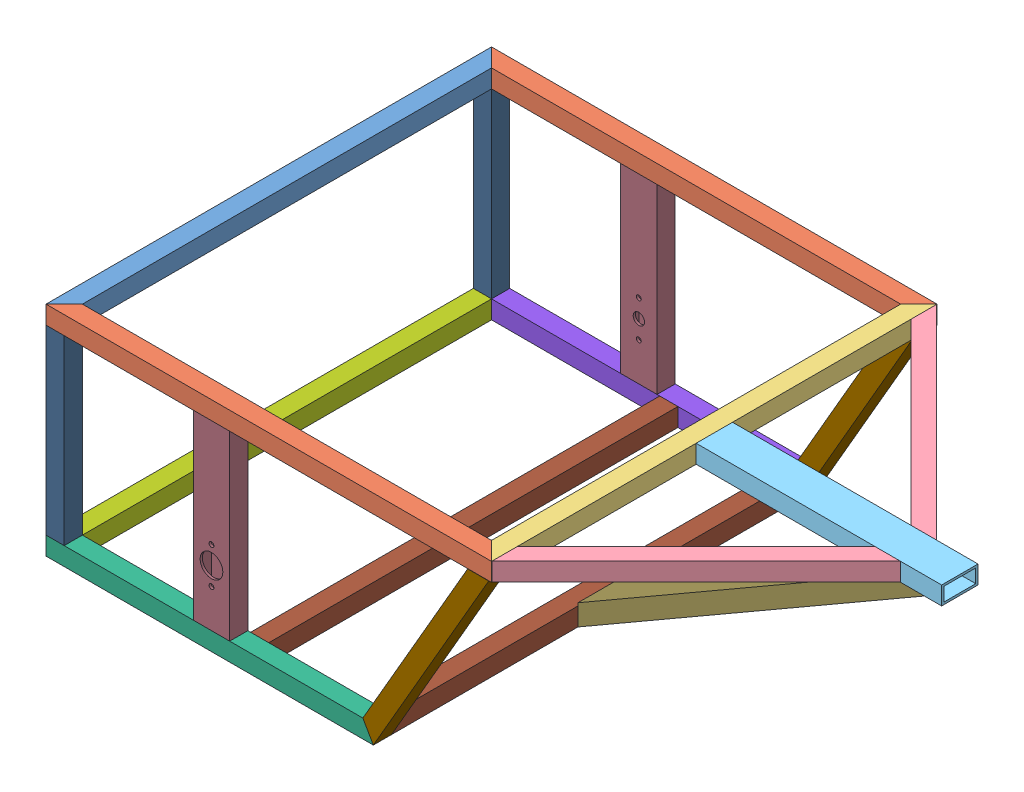
SolidWorks assembly chassis, configuration Default. Lengths in mm.
Overall size (965.2 304.8 622.3).
21 component instances, 13 part files, 0 mates.
Components (placement in the parent):
- chassis weldment top-1-1: chassis weldment top-1 [Default] at (64.6916 38.689 -16.8871) size (965.2 25.4 622.3)
  - frame member front-11-1: frame member front-11 [Default] at origin size (25.4 25.4 622.3)
  - frame member side-11-1: frame member side-11 [Default] at (298.45 0 298.45) x (0 0 1) z (-1 0 0) size (25.4 25.4 622.3)
  - frame member side-11-2: frame member side-11 [Default] at (298.45 0 -298.45) x (0 0 -1) z (-1 0 0) size (25.4 25.4 622.3)
  - frame member crossbrace middle-11-1: frame member crossbrace middle-11 [Default] at (596.9 0 0) x (-1 0 0) z (0 0 1) size (25.4 25.4 622.3)
  - frame member back angle-11-1: frame member back angle-11 [Default] at (743.1813 0 -158.9813) x (-0.707107 0 0.707107) z (-0.707107 0 -0.707107) size (25.4 25.4 403.23)
  - frame member back angle-11-2: frame member back angle-11 [Default] at (743.1813 0 158.9813) x (-0.707107 0 -0.707107) z (-0.707107 0 0.707107) size (25.4 25.4 403.23)
  - frame member back center-11-1: frame member back center-11 [Default] at (781.05 0 0) x (0 0 -1) z (1 0 0) size (50.8 25.4 342.9)
- chassis weldment bottom-1-1: chassis weldment bottom-1 [Default] at (280.5916 -240.711 281.5629) x (0 -1 0) z (-1 0 0) size (301.4 622.3 941.13)
  - bottom frame member side-1-1: bottom frame member side-1 [Default] at origin size (25.4 25.4 457.2)
  - bottom frame member crossbrace-1-1: bottom frame member crossbrace-1 [Default] at (0 -298.45 215.9) x (0 0 -1) z (0 1 0) size (25.4 25.4 622.3)
  - bottom frame member side_MIR-1-1: bottom frame member side_MIR-1 [Default] at (0 -596.9 0) x (1 0 0) z (0 0 -1) size (25.4 25.4 457.2)
  - bottom frame member angle-1-1: bottom frame member angle-1 [Default] at (-133.1938 -596.9 -298.1671) x (0.5 0 -0.866025) z (0.866025 0 0.5) size (25.4 25.4 322.26)
  - bottom frame member angle-1-2: bottom frame member angle-1 [Default] at (-133.1938 0 -298.1671) x (0.5 0 -0.866025) z (0.866025 0 0.5) size (25.4 25.4 322.26)
  - bottom frame member back upright-1-1: bottom frame member back upright-1 [Default] at (-139.7 -596.9 215.9) x (0 0 -1) z (1 0 0) size (25.4 25.4 254)
  - bottom frame member back upright-1-2: bottom frame member back upright-1 [Default] at (-139.7 0 215.9) x (0 0 -1) z (1 0 0) size (25.4 25.4 254)
  - bottom frame member crossbrace back-1-1: bottom frame member crossbrace back-1 [Default] at (0 -298.45 -215.9) x (1 0 0) z (0 -1 0) size (25.4 25.4 571.5)
  - bottom frame member brace-1-1: bottom frame member brace-1 [Default] at (-137.9985 -298.45 -464.2175) x (0 1 0) z (0.5 0 0.866025) size (50.8 25.4 558.8)
  - bottom frame member crossbrace back-1-2: bottom frame member crossbrace back-1 [Default] at (0 -298.45 -44.45) x (1 0 0) z (0 1 0) size (25.4 25.4 571.5)
  - wheel mount vertical-1-1: wheel mount vertical-1 [Default] at (-139.7 -596.9 -2.54) x (0 0 1) z (1 0 0) size (50.8 25.4 254)
  - wheel mount vertical-1-2: wheel mount vertical-1 [Default] at (-139.7 0 -2.54) x (0 0 -1) z (1 0 0) size (50.8 25.4 254)
